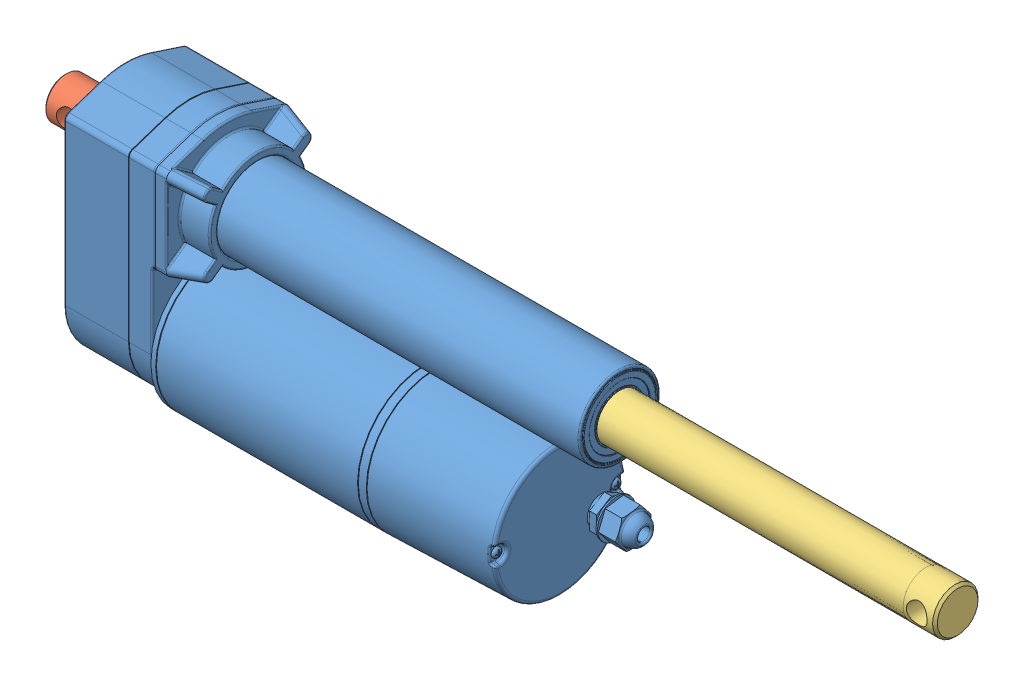
SolidWorks assembly NIA5_115_40_B_153, configuration Valor predeterminado. Lengths in mm.
Overall size (561.56 156.6 87).
3 component instances, 3 part files, 4 mates.
Components (placement in the parent):
- NIA5 Housing_00-1: NIA5 Housing_00 [Valor predeterminado] at origin size (320.79 156.6 87)
- BaseClevis-1: BaseClevis [Valor predeterminado] at (-9 75.1 0) x (0 0 -1) z (0 1 0) size (26 29 26)
- ND8 Rod_00-1: ND8 Rod_00 [Valor predeterminado] at (247.8589 75.1 0) x (1 0 0) z (0 0 -1) size (275.7 38 38)
Mates (geometry in assembly coordinates):
- Concêntrico1: concentric aligned: cylinder of NIA5 Housing_00-1 through (400.342 75.1 0) axis (-1 0 0) radius 14.5; cylinder of ND8 Rod_00-1 through (552.364 75.1 0) axis (-1 0 0) radius 14.25
- Concêntrico2: concentric anti-aligned: cylinder of BaseClevis-1 through (-38 75.1 0) axis (1 0 0) radius 13; cylinder of ND8 Rod_00-1 through (552.364 75.1 0) axis (-1 0 0) radius 14.25
- Coincidente1: coincident anti-aligned: plane of NIA5 Housing_00-1 through (-9 75.1 0) normal (-1 0 0); plane of BaseClevis-1 through (-9 75.1 0) normal (1 0 0)
- Coincidente3: coincident anti-aligned: plane of ND8 Rod_00-1 through (247.8589 75.1 0) normal (0 0 -1); plane of assembly
